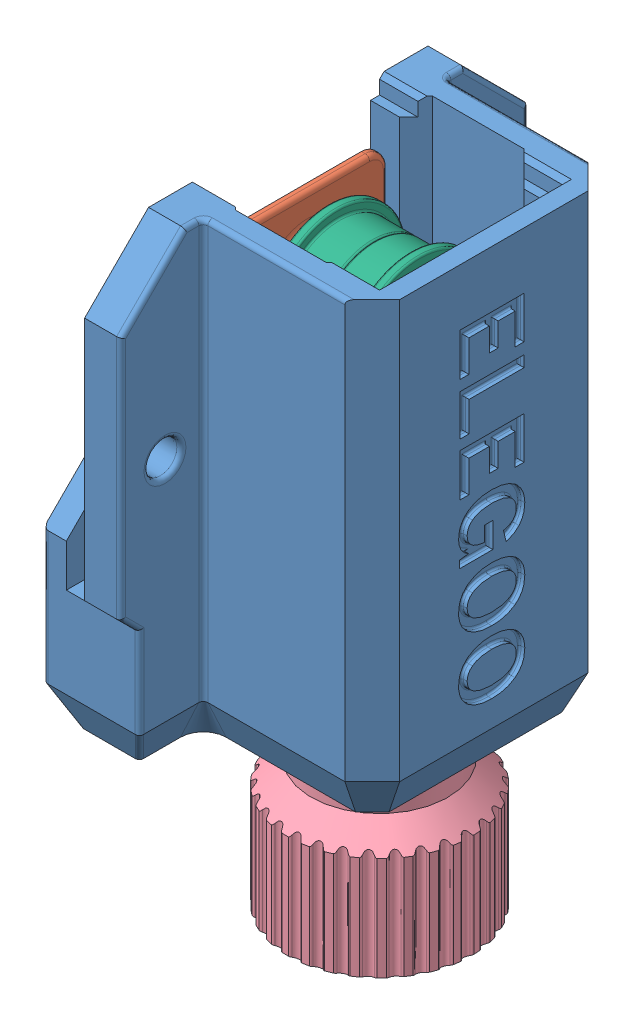
SolidWorks assembly 张紧器组件, configuration 默认. Lengths in mm.
Overall size (29 70.18 44.6).
7 component instances, 6 part files, 10 mates.
Components (placement in the parent):
- 张紧器外壳-1: 张紧器外壳 [默认] at (-0.5373 17.7615 44.6) size (29 50 44.6)
- 张紧器滑块-1: 张紧器滑块 [默认] at (-1.7873 12.6584 44.6) x (1 0 0) z (0 -1 0) size (19.5 17.5 26)
- 销钉-2: 销钉 [默认] at (-11.5373 5.1584 44.6) x (0 0 -1) z (1 0 0) size (3.45 3.8 18)
- 手拧螺钉L10-1: 手拧螺钉L10 [Default] at (-1.7873 -52.5843 44.6) x (0.035585 0 -0.999367) z (0.999367 0 0.035585) size (20.01 19.84 20)
- 内六角圆柱头螺钉M4X35-1: 内六角圆柱头螺钉M4X35 [默认] at (-1.7873 -6.3416 44.6) x (0 -1 0) z (0 0 1) size (39 7 7)
- 轴承-1: 轴承 [默认] at (2.6242 5.1584 44.6) x (0 0 1) z (-1 0 0) size (15 15 5)
- 轴承-2: 轴承 [默认] at (-7.3758 5.1584 44.6) x (0 0 -1) z (1 0 0) size (15 15 5)
Mates (geometry in assembly coordinates):
- 同心1: concentric aligned: cylinder of 张紧器外壳-1 through (-1.7873 -19.2385 44.6) axis (0 1 0) radius 2.35; cylinder of 张紧器滑块-1 through (-1.7873 -13.3416 44.6) axis (0 1 0) radius 1.8
- 同心3: concentric aligned: circle of 张紧器滑块-1; cylinder of 销钉-2 through (6.4627 5.1584 44.6) axis (-1 0 0) radius 1.9
- 重合1: coincident aligned: plane of 张紧器滑块-1 through (-11.5373 -13.3416 53.35) normal (-1 0 0); plane of 销钉-2 through (-11.5373 5.1584 44.6) normal (-1 0 0)
- 同心4: concentric aligned: cylinder of 张紧器外壳-1 through (-1.7873 -19.2385 44.6) axis (0 1 0) radius 2.35; cylinder of 手拧螺钉L10-1 through (-1.7873 -52.5843 44.6) axis (0 1 0) radius 1.825
- 同心5: concentric aligned: cylinder of 张紧器滑块-1 through (-1.7873 -13.3416 44.6) axis (0 1 0) radius 1.8; cylinder of 内六角圆柱头螺钉M4X35-1 through (-1.7873 -6.3416 44.6) axis (0 1 0) radius 2
- 重合2: coincident anti-aligned: plane of 张紧器滑块-1 through (-1.7873 -10.3416 44.6) normal (0 1 0); plane of 内六角圆柱头螺钉M4X35-1 through (1.7127 -10.3416 44.6) normal (0 -1 0)
- 同心6: concentric anti-aligned: cylinder of 销钉-2 through (6.4627 5.1584 44.6) axis (-1 0 0) radius 1.9; cylinder of 轴承-1 through (-2.3758 5.1584 44.6) axis (1 0 0) radius 2.5
- 距离1: distance = 0.25 mm anti-aligned: plane of 轴承-1 through (2.6242 5.1584 44.6) normal (1 0 0); plane of 张紧器滑块-1 through (2.8742 -7.3416 35.85) normal (-1 0 0)
- 同心7: concentric aligned: cylinder of 销钉-2 through (6.4627 5.1584 44.6) axis (-1 0 0) radius 1.9; cylinder of 轴承-2 through (-2.3758 5.1584 44.6) axis (-1 0 0) radius 2.5
- 重合5: coincident anti-aligned: plane of 轴承-1 through (-2.3758 5.1584 44.6) normal (-1 0 0); circle of 轴承-2
